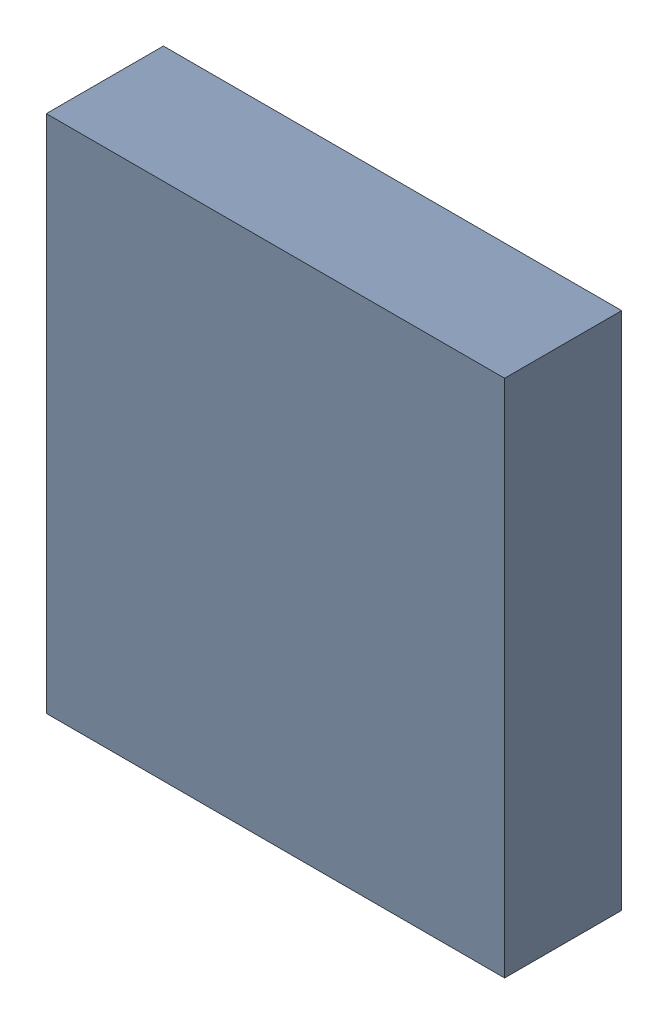
SolidWorks assembly U500_1PCB, configuration Default. Lengths in mm.
Overall size (4.5 5.1 1.15).
2 component instances, 1 part files, 0 mates.
Components (placement in the parent):
- 846483832-1: 846483832 [Default] at (151.9 117.8 0.05) size (4.5 5.1 1.15)
  - Extruded_18-1: Extruded_18 [Default] at origin size (4.5 5.1 1.15)
